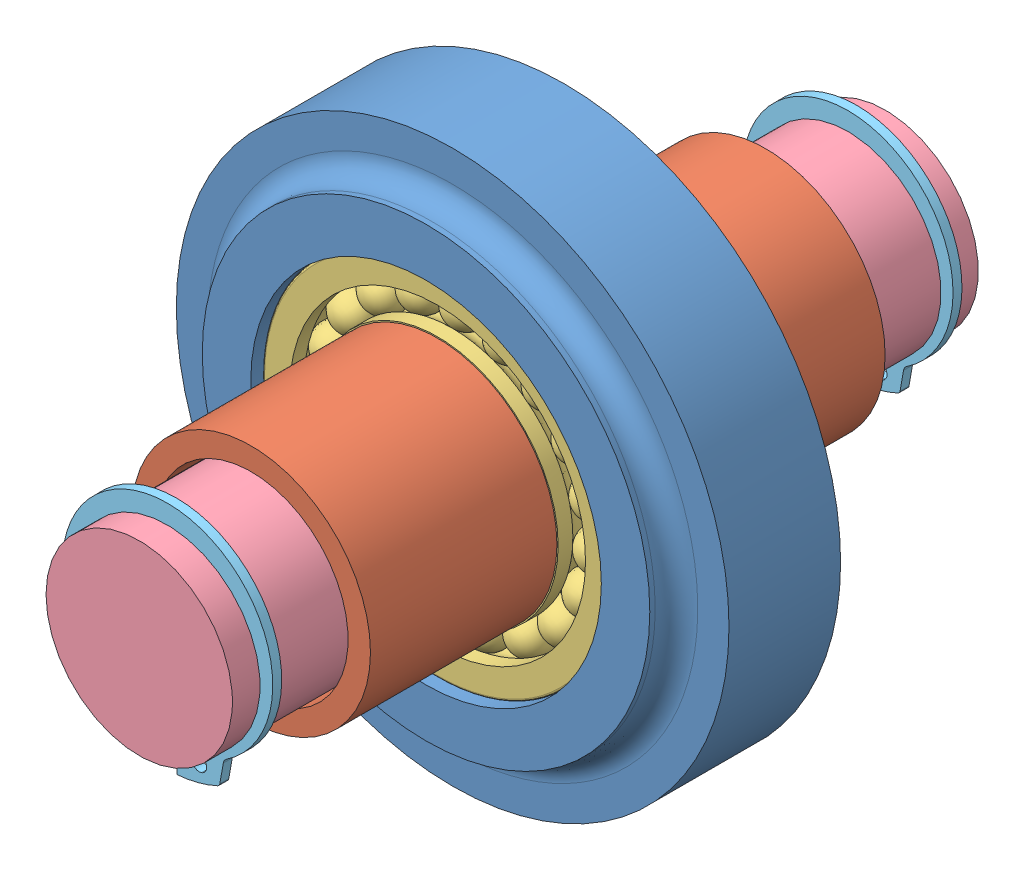
SolidWorks assembly 16A托轮装配, configuration 默认. Lengths in mm.
Overall size (74.1 74.1 100).
8 component instances, 5 part files, 14 mates.
Components (placement in the parent):
- 单排托轮16A-11-1: 单排托轮16A-11 [16A] at (1189.3075 572.0195 5409.7552) x (0 0 1) z (-1 0 0) size (22.1 74.1 74.1)
- 16A转向轮轴套-1: 16A转向轮轴套 [默认] at (1189.3075 572.0195 5419.2552) size (32 32 25)
- 16A转向轮轴套-2: 16A转向轮轴套 [默认] at (1189.3075 572.0195 5375.2552) size (32 32 25)
- deep groove ball bearings gb-1: deep groove ball bearings gb [Rolling bearings 16005 GB 276-94] at (1189.3075 572.0195 5415.2552) x (0 0 1) z (-1 0 0) size (8 47 47)
- deep groove ball bearings gb-2: deep groove ball bearings gb [Rolling bearings 16005 GB 276-94] at (1189.3075 572.0195 5404.2552) x (0 0 -1) z (1 0 0) size (8 47 47)
- 转向轮轴-1: 转向轮轴 [默认] at (-120.0173 -164.6161 -48.7448) size (25 25 100)
- circlips for shaft--type a large gb-1: circlips for shaft--type a large gb [GB_CONNECTING_PIECE_RING_RRA 25] at (1189.3075 572.8495 5364.2552) size (28.2 30.88 1.2)
- circlips for shaft--type a large gb-2: circlips for shaft--type a large gb [GB_CONNECTING_PIECE_RING_RRA 25] at (1189.3075 572.8495 5455.4552) size (28.2 30.88 1.2)
Mates (geometry in assembly coordinates):
- 同心11: concentric: cylinder of 单排托轮16A-11-1 through (1189.3075 572.0195 5398.7048) axis (0 0 1) radius 23.5; cylinder of deep groove ball bearings gb-1 through (1189.3075 572.0195 5406.5445) axis (0 0 -1) radius 23.5
- 同心12: concentric: cylinder of 单排托轮16A-11-1 through (1189.3075 572.0195 5398.7048) axis (0 0 1) radius 23.5; cylinder of deep groove ball bearings gb-2 through (1189.3075 572.0195 5412.9658) axis (0 0 1) radius 23.5
- 重合11: coincident: plane of 单排托轮16A-11-1 through (1189.3075 572.0195 5411.2552) normal (0 0 1); plane of deep groove ball bearings gb-1 through (1189.3075 595.5195 5411.2552) normal (0 0 -1)
- 重合12: coincident: plane of 单排托轮16A-11-1 through (1189.3075 572.0195 5408.2552) normal (0 0 -1); plane of deep groove ball bearings gb-2 through (1189.3075 595.5195 5408.2552) normal (0 0 1)
- 同心13: concentric: cylinder of deep groove ball bearings gb-1 through (1189.3075 572.0195 5408.2838) axis (0 0 -1) radius 12.5; cylinder of 16A转向轮轴套-1 through (1189.3075 572.0195 5444.2552) axis (0 0 -1) radius 13
- 重合13: coincident: plane of deep groove ball bearings gb-1 through (1189.3075 584.5195 5419.2552) normal (0 0 1); plane of 16A转向轮轴套-1 through (1189.3075 572.0195 5419.2552) normal (0 0 -1)
- 同心14: concentric: cylinder of deep groove ball bearings gb-2 through (1189.3075 572.0195 5411.2265) axis (0 0 1) radius 12.5; cylinder of 16A转向轮轴套-2 through (1189.3075 572.0195 5400.2552) axis (0 0 -1) radius 13
- 重合14: coincident: plane of deep groove ball bearings gb-2 through (1189.3075 584.5195 5400.2552) normal (0 0 -1); plane of 16A转向轮轴套-2 through (1189.3075 572.0195 5400.2552) normal (0 0 1)
- 同心15: concentric: cylinder of 转向轮轴-1 through (1189.3075 572.0195 5459.2552) axis (0 0 -1) radius 12.5; cylinder of deep groove ball bearings gb-1 through (1189.3075 572.0195 5408.2838) axis (0 0 -1) radius 12.5
- 距离1: distance = 15 mm: plane of 转向轮轴-1 through (1189.3075 572.0195 5459.2552) normal (0 0 1); plane of 16A转向轮轴套-1 through (1189.3075 572.0195 5444.2552) normal (0 0 1)
- 同心16: concentric: cylinder of 转向轮轴-1 through (1189.3075 572.0195 5362.9552) axis (0 0 1) radius 11.45; cylinder of circlips for shaft--type a large gb-1 through (1189.3075 572.0195 5363.0552) axis (0 0 1) radius 11.6
- 重合15: coincident: plane of 转向轮轴-1 through (1189.3075 572.0195 5364.2552) normal (0 0 -1); plane of circlips for shaft--type a large gb-1 through (1189.3075 572.0195 5364.2552) normal (0 0 1)
- 重合16: coincident: plane of 转向轮轴-1 through (1189.3075 572.0195 5454.2552) normal (0 0 1); plane of circlips for shaft--type a large gb-2 through (1189.3075 572.0195 5454.2552) normal (0 0 -1)
- 同心18: concentric: cylinder of 转向轮轴-1 through (1189.3075 572.0195 5455.5552) axis (0 0 -1) radius 11.45; cylinder of circlips for shaft--type a large gb-2 through (1189.3075 572.0195 5454.2552) axis (0 0 1) radius 11.6
